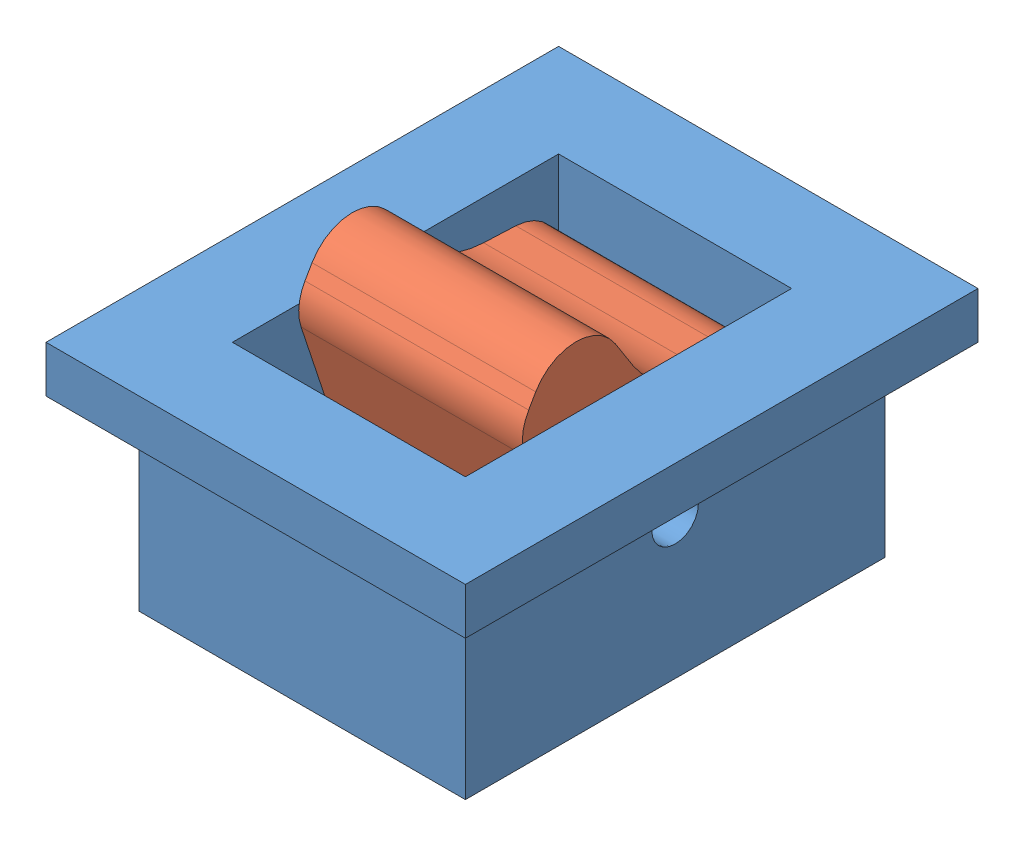
SolidWorks assembly Assem3, configuration Default. Lengths in mm.
Overall size (11.43 8.37 13.97).
2 component instances, 2 part files, 3 mates.
Components (placement in the parent):
- Switch_Housing-1: Switch_Housing [Default] at origin size (11.43 6.35 13.97)
- Switch-1: Switch [Default] at (0 3.81 0) x (1 0 0) z (0 0.5 0.866025) size (6.1 4.97 7.62)
Mates (geometry in assembly coordinates):
- Concentric1: concentric aligned: cylinder of Switch_Housing-1 through (5.715 3.81 0) axis (-1 0 0) radius 0.635; cylinder of Switch-1 through (3.048 3.81 0) axis (-1 0 0) radius 0.635
- Width1: width anti-aligned: plane of Switch_Housing-1 through (-3.175 6.35 4.445) normal (1 0 0); plane of Switch_Housing-1 through (3.175 6.35 4.445) normal (-1 0 0); plane of Switch-1 through (-3.048 3.81 0) normal (-1 0 0); plane of Switch-1 through (3.048 3.81 0) normal (1 0 0)
- LimitAngle1: limit planar angle = 1.047198 rad aligned: plane of Switch_Housing-1 through (0 6.35 0) normal (0 1 0); plane of Switch-1 through (0 3.81 0) normal (0 0.5 0.866025)
